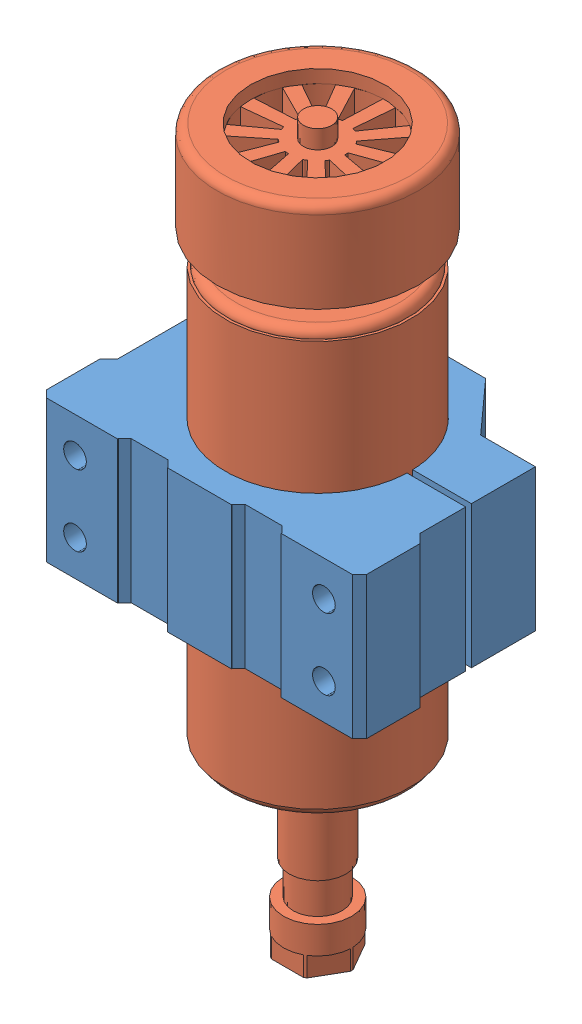
SolidWorks assembly motor, configuration Default. Lengths in mm.
Overall size (90 203.08 66.5).
2 component instances, 2 part files, 2 mates.
Components (placement in the parent):
- Mount-1: Mount [Default] at (63.5908 7.8878 -93.3042) size (90 40 66.5)
- SpindleFull-1: SpindleFull [Default] at (63.5908 54.6679 -93.3042) size (56.5 203.08 56.5)
Mates (geometry in assembly coordinates):
- Concentric3: concentric anti-aligned: cylinder of Mount-1 through (63.5908 47.8878 -93.3042) axis (0 -1 0) radius 26; cylinder of SpindleFull-1 through (63.5908 121.1712 -93.3042) axis (0 1 0) radius 26
- Width2: width anti-aligned: plane of SpindleFull-1 through (50.5908 87.3878 -93.3042) normal (0 1 0); plane of SpindleFull-1 through (40.6908 -31.6122 -93.3042) normal (0 -1 0); plane of Mount-1 through (63.5908 7.8878 -93.3042) normal (0 -1 0); plane of Mount-1 through (63.5908 47.8878 -93.3042) normal (0 1 0)
